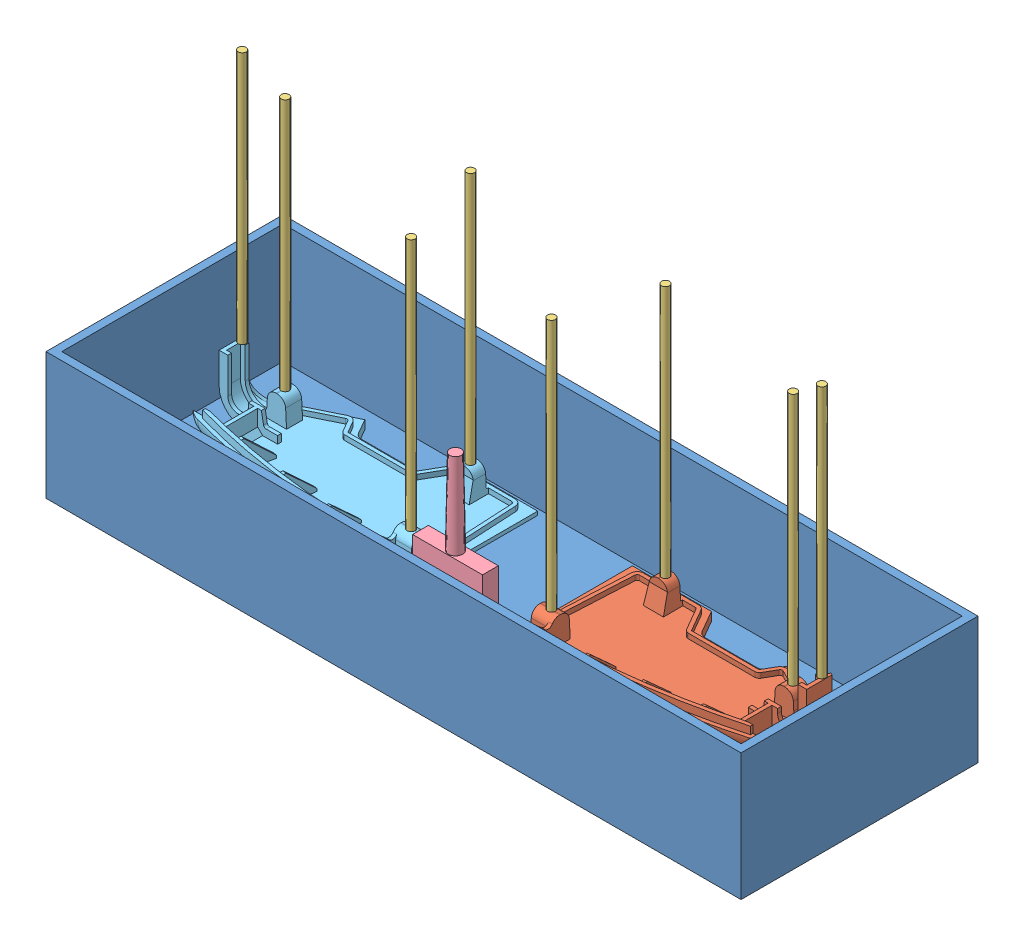
SolidWorks assembly MOLD, CHASSIS, FRONT, LEFT WALL, configuration Default. Lengths in mm.
Overall size (279.4 139.97 95.25).
15 component instances, 8 part files, 23 mates.
Components (placement in the parent):
- MOLD, CHASSIS, FRONT, LEFT WALL-1: MOLD, CHASSIS, FRONT, LEFT WALL [Default] at (-128.4874 -0.9861 35.8337) size (279.4 51.08 95.25)
- CHASSIS, UNIBODY, FRONT, LEFT WALL-1: CHASSIS, UNIBODY, FRONT, LEFT WALL [Default] at (-109.4374 76.4839 6.4602) x (1 0 0) z (0 -1 0) size (99.06 55.63 24.5)
- MOLD, POURING VENT-1: MOLD, POURING VENT [Default] at (-88.9829 26.8889 13.6343) size (3.17 101.6 3.17)
- MOLD, POURING VENT-2: MOLD, POURING VENT [Default] at (-25.8301 26.8889 25.4735) size (3.17 101.6 3.17)
- MOLD, POURING VENT-3: MOLD, POURING VENT [Default] at (-100.178 26.8889 48.2794) size (3.17 101.6 3.17)
- MOLD, POURING VENT-4: MOLD, POURING VENT [Default] at (-12.1553 37.3889 27.6142) size (3.17 101.6 3.17)
- MOLD, CHASSIS, FRONT, LEFT WALL, SUPPORT-1: MOLD, CHASSIS, FRONT, LEFT WALL, SUPPORT [Default] at (-109.4374 37.3889 6.4602) x (-1 0 0) z (0 1 0) (suppressed, hidden)
- MOLD, Box, FRONT, LEFT WALL, Support Base-1: MOLD, Box, FRONT, LEFT WALL, Support Base [Default] at (-63.4391 39.9764 34.1459) x (-1 0 0) z (0 0 1) (suppressed, hidden)
- MOLD, CHASSIS, FRONT, LEFT WALL, SUPPORT, MIRROR-2: MOLD, CHASSIS, FRONT, LEFT WALL, SUPPORT, MIRROR [Default] at (-147.5374 37.3889 6.4602) x (1 0 0) z (0 -1 0) (suppressed, hidden)
- MOLD, CHASSIS, FRONT, LEFT WALL, SPRUE, T-1: MOLD, CHASSIS, FRONT, LEFT WALL, SPRUE, T [Default] at (-128.4874 21.7139 58.5612) size (38.1 53.97 6.35)
- CHASSIS, UNIBODY, FRONT, LEFT WALL, MIRROR-1: CHASSIS, UNIBODY, FRONT, LEFT WALL, MIRROR [Default] at (-147.5374 76.4839 6.4602) x (-1 0 0) z (0 1 0) size (99.06 55.63 24.5)
- MOLD, POURING VENT-5: MOLD, POURING VENT [Default] at (-244.9955 37.3889 27.7946) size (3.17 101.6 3.17)
- MOLD, POURING VENT-6: MOLD, POURING VENT [Default] at (-167.5294 26.8889 13.428) size (3.17 101.6 3.17)
- MOLD, POURING VENT-7: MOLD, POURING VENT [Default] at (-156.414 26.8889 48.4467) size (3.17 101.6 3.17)
- MOLD, POURING VENT-8: MOLD, POURING VENT [Default] at (-230.4439 26.8889 25.0531) size (3.17 101.6 3.17)
Mates (geometry in assembly coordinates):
- Distance1: distance = 12.7 mm anti-aligned: plane of CHASSIS, UNIBODY, FRONT, LEFT WALL-1 through (-96.7374 14.8889 -236.6869) normal (0 -1 0); plane of MOLD, CHASSIS, FRONT, LEFT WALL-1 through (11.2126 2.1889 -11.7913) normal (0 1 0)
- Coincident2: coincident anti-aligned: plane of CHASSIS, UNIBODY, FRONT, LEFT WALL-1 through (-85.9374 26.8889 11.0602) normal (0 1 0); plane of MOLD, POURING VENT-1 through (-88.9829 26.8889 13.6343) normal (0 -1 0)
- Coincident3: coincident anti-aligned: plane of CHASSIS, UNIBODY, FRONT, LEFT WALL-1 through (-10.3816 37.3889 33.9602) normal (0 1 0); plane of MOLD, POURING VENT-4 through (-12.1553 37.3889 27.6142) normal (0 -1 0)
- Coincident6: coincident anti-aligned: plane of CHASSIS, UNIBODY, FRONT, LEFT WALL-1 through (-96.4978 26.8889 44.9602) normal (0 1 0); plane of MOLD, POURING VENT-2 through (-25.8301 26.8889 25.4735) normal (0 -1 0)
- Coincident7: coincident aligned: plane of MOLD, POURING VENT-1 through (-88.9829 128.4889 13.6343) normal (0 1 0); plane of MOLD, POURING VENT-3 through (-100.178 128.4889 48.2794) normal (0 1 0)
- Coincident8: coincident aligned: plane of CHASSIS, UNIBODY, FRONT, LEFT WALL-1 through (-96.7374 27.8889 -236.6869) normal (0 1 0); plane of MOLD, CHASSIS, FRONT, LEFT WALL, SUPPORT-1 through (-96.7374 27.8889 -236.6869) normal (0 1 0)
- Coincident9: coincident aligned: plane of CHASSIS, UNIBODY, FRONT, LEFT WALL-1 through (-107.5374 -499923.5161 55.3862) normal (-0.99863 0 -0.052336); plane of MOLD, CHASSIS, FRONT, LEFT WALL, SUPPORT-1 through (-107.5374 -499923.5161 55.3862) normal (-0.99863 0 -0.052336)
- Coincident10: coincident aligned: plane of CHASSIS, UNIBODY, FRONT, LEFT WALL-1 through (-69.9553 18.3889 19.1702) normal (0 0 -1); plane of MOLD, CHASSIS, FRONT, LEFT WALL, SUPPORT-1 through (-69.9553 18.3889 19.1702) normal (0 0 -1)
- Coincident11: coincident anti-aligned: plane of MOLD, CHASSIS, FRONT, LEFT WALL, SUPPORT-1 through (-59.9095 38.3889 -64.8679) normal (0 1 0); plane of MOLD, Box, FRONT, LEFT WALL, Support Base-1 through (-130.1141 38.3889 -10.3041) normal (0 -1 0)
- Width1: width anti-aligned: plane of MOLD, Box, FRONT, LEFT WALL, Support Base-1 through (3.2359 38.3889 -10.3041) normal (0 0 -1); plane of MOLD, Box, FRONT, LEFT WALL, Support Base-1 through (3.2359 38.3889 78.5959) normal (0 0 1); plane of MOLD, CHASSIS, FRONT, LEFT WALL-1 through (21.946 50.0933 -8.4856) normal (0 0 1); plane of MOLD, CHASSIS, FRONT, LEFT WALL-1 through (-289.204 50.0933 80.4144) normal (0 0 -1)
- Width2: width aligned: plane of CHASSIS, UNIBODY, FRONT, LEFT WALL, MIRROR-1 through (-246.5931 37.3889 35.4602) normal (-1 0 0); plane of CHASSIS, UNIBODY, FRONT, LEFT WALL-1 through (-10.3816 37.3889 35.4602) normal (1 0 0); plane of MOLD, CHASSIS, FRONT, LEFT WALL-1 through (-265.0124 50.0933 -8.6163) normal (1 0 0); plane of MOLD, CHASSIS, FRONT, LEFT WALL-1 through (8.0376 50.0933 80.2837) normal (-1 0 0)
- Coincident12: coincident anti-aligned: plane of MOLD, CHASSIS, FRONT, LEFT WALL, SUPPORT, MIRROR-2 through (-147.5374 14.8889 62.0862) normal (1 0 0); plane of MOLD, CHASSIS, FRONT, LEFT WALL, SPRUE, T-1 through (-147.5374 21.7139 58.5612) normal (-1 0 0)
- Coincident13: coincident anti-aligned: plane of MOLD, CHASSIS, FRONT, LEFT WALL, SUPPORT-1 through (-59.9095 24.8889 -38.2705) normal (0 -1 0); plane of MOLD, CHASSIS, FRONT, LEFT WALL, SPRUE, T-1 through (-109.4374 24.8889 61.7362) normal (0 1 0)
- Coincident14: coincident anti-aligned: plane of MOLD, CHASSIS, FRONT, LEFT WALL, SUPPORT-1 through (-97.8805 8.0616 55.3862) normal (0 0 1); plane of MOLD, CHASSIS, FRONT, LEFT WALL, SPRUE, T-1 through (-109.4374 24.8889 55.3862) normal (0 0 -1)
- Coincident15: coincident aligned: plane of CHASSIS, UNIBODY, FRONT, LEFT WALL-1 through (-96.7374 14.8889 -236.6869) normal (0 -1 0); plane of CHASSIS, UNIBODY, FRONT, LEFT WALL, MIRROR-1 through (-160.2374 14.8889 -236.6869) normal (0 -1 0)
- Coincident17: coincident aligned: plane of CHASSIS, UNIBODY, FRONT, LEFT WALL-1 through (-109.4374 14.8889 6.4602) normal (0 0 -1); plane of CHASSIS, UNIBODY, FRONT, LEFT WALL, MIRROR-1 through (-147.5374 14.8889 6.4602) normal (0 0 -1)
- Coincident18: coincident anti-aligned: plane of MOLD, CHASSIS, FRONT, LEFT WALL, SPRUE, T-1 through (-147.5374 21.7139 58.5612) normal (-1 0 0); plane of CHASSIS, UNIBODY, FRONT, LEFT WALL, MIRROR-1 through (-147.5374 14.8889 62.0862) normal (1 0 0)
- Coincident19: coincident anti-aligned: plane of CHASSIS, UNIBODY, FRONT, LEFT WALL, MIRROR-1 through (-171.0374 26.8889 11.0602) normal (0 1 0); plane of MOLD, POURING VENT-6 through (-167.5294 26.8889 13.428) normal (0 -1 0)
- Coincident20: coincident anti-aligned: plane of CHASSIS, UNIBODY, FRONT, LEFT WALL-1 through (-109.4374 14.8889 62.0862) normal (-1 0 0); plane of MOLD, CHASSIS, FRONT, LEFT WALL, SPRUE, T-1 through (-109.4374 21.7139 58.5612) normal (1 0 0)
- Coincident21: coincident anti-aligned: plane of CHASSIS, UNIBODY, FRONT, LEFT WALL, MIRROR-1 through (-246.5931 37.3889 33.9602) normal (0 1 0); plane of MOLD, POURING VENT-5 through (-244.9955 37.3889 27.7946) normal (0 -1 0)
- Coincident22: coincident anti-aligned: plane of CHASSIS, UNIBODY, FRONT, LEFT WALL, MIRROR-1 through (-234.0374 26.8889 22.0102) normal (0 1 0); plane of MOLD, POURING VENT-8 through (-230.4439 26.8889 25.0531) normal (0 -1 0)
- Coincident23: coincident anti-aligned: plane of CHASSIS, UNIBODY, FRONT, LEFT WALL, MIRROR-1 through (-160.4769 26.8889 44.9602) normal (0 1 0); plane of MOLD, POURING VENT-7 through (-156.414 26.8889 48.4467) normal (0 -1 0)
- PLANE1: unknown = 19.05 mm: plane of CHASSIS, UNIBODY, FRONT, LEFT WALL-1 through (-109.4374 14.8889 62.0862) normal (-1 0 0)
